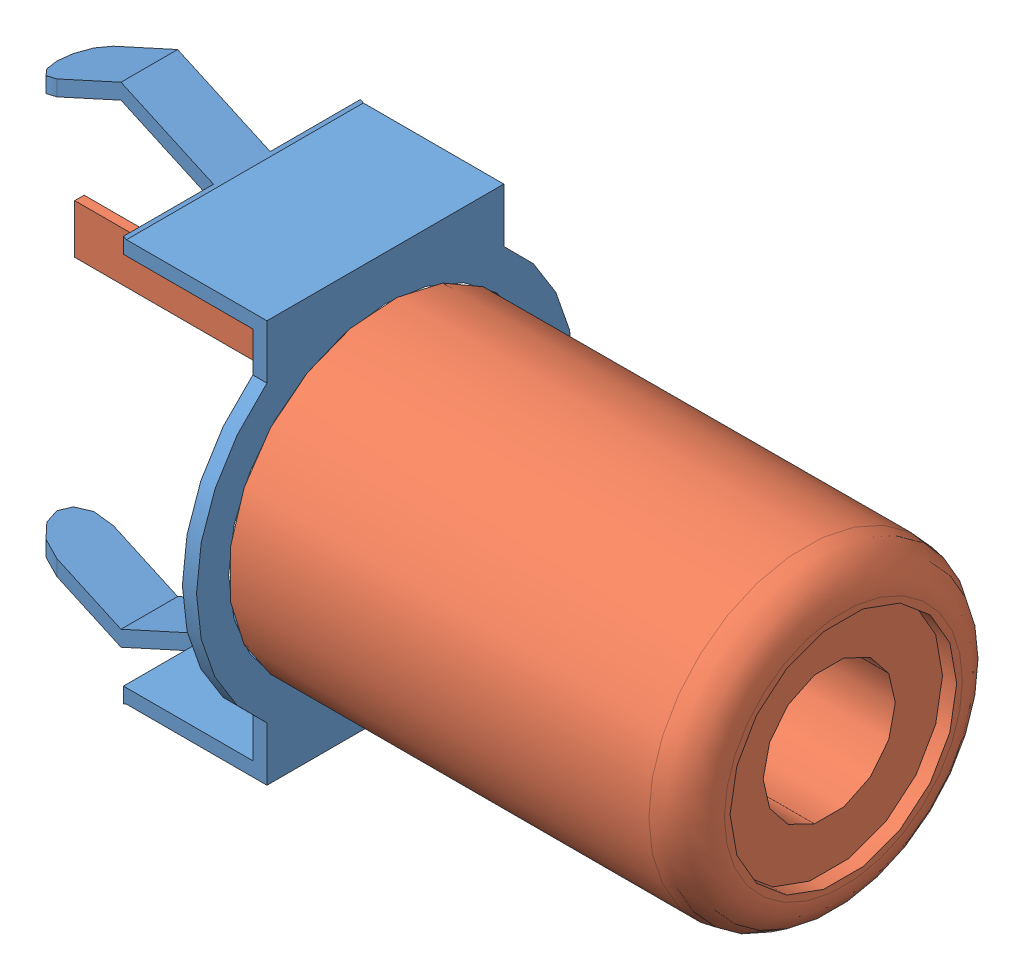
SolidWorks assembly rcj-021, configuration Default. Lengths in mm.
Overall size (22.1 12.95 10).
2 component instances, 2 part files, 0 mates.
Components (placement in the parent):
- rcj-021_01-1: rcj-021_01 [Default] at (-3.5 0 0) size (8.7 12.95 10)
- rcj-021_02-1: rcj-021_02 [Default] at (-3.5 0 0) size (22.1 8.3 8.3)
